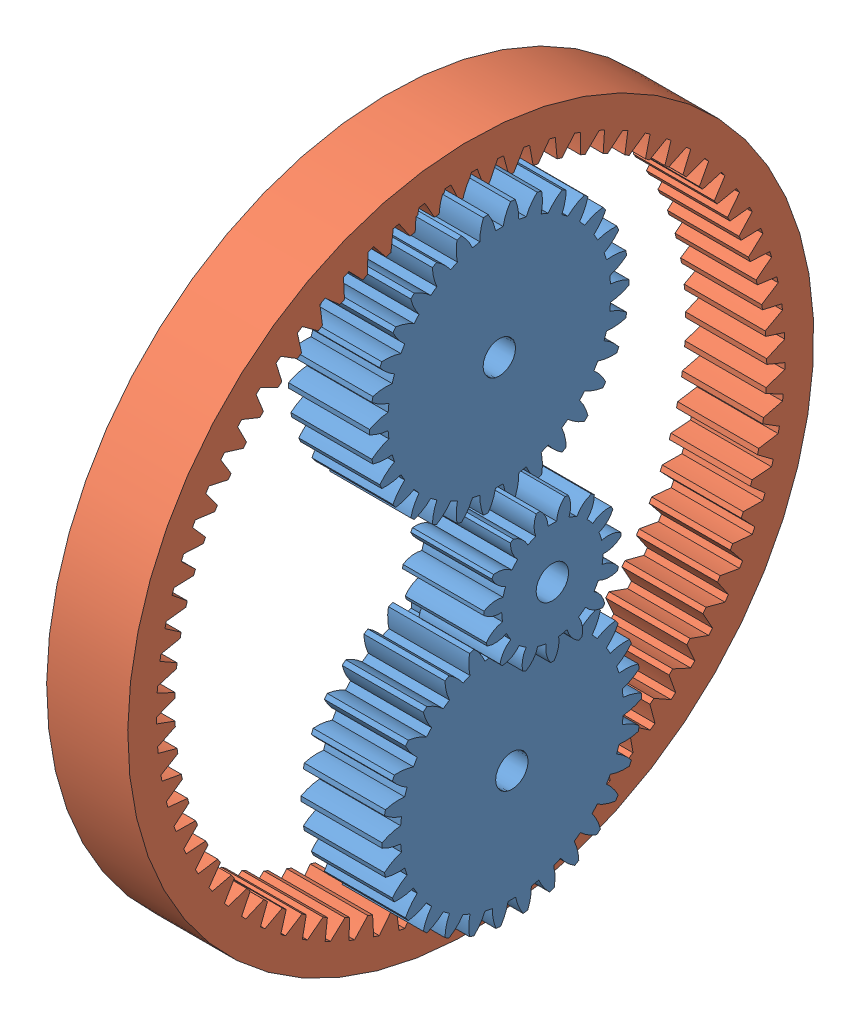
SolidWorks assembly Assem3, configuration Default. Lengths in mm.
Overall size (10 58.23 58.23).
4 component instances, 2 part files, 4 mates.
Components (placement in the parent):
- spur gear_am-1: spur gear_am [Metric - Spur gear 0.5M 15T 20PA 5FW ---S15N75H50L2N] at (-0.0365 -6.3386 28.5198) size (5 8.43 8.47)
- internal spur gear_am-2: internal spur gear_am [Metric - Internal spur gear 0.5M 75T 20PA 5FW ---S75S42.3OD 1AF] at (-0.0365 -6.3452 28.5512) x (-1 0 0) z (0 -0.850414 -0.526114) size (5 42.3 42.3)
- spur gear_am-3: spur gear_am [Metric - Spur gear 0.5M 30T 20PA 5FW ---S30N75H50L2N] at (-2.5182 4.8152 29.308) size (5 15.94 16)
- spur gear_am-4: spur gear_am [Metric - Spur gear 0.5M 30T 20PA 5FW ---S30N75H50L2N] at (-2.5182 -17.6397 28.5353) size (5 15.94 16)
Mates (geometry in assembly coordinates):
- Coincident1: coincident: plane of spur gear_am-1 through (-0.0365 -6.3386 28.5198) normal (-1 0 0); plane of internal spur gear_am-2 through (-0.0365 9.1748 38.1528) normal (1 0 0)
- GearMate1: gear = 2 : 2 mm: circle of spur gear_am-4; circle of spur gear_am-1
- GearMate2: gear = 2 : 2 mm: circle of spur gear_am-1; circle of spur gear_am-3
- GearMate3: gear = 2 : 42.3 mm: circle of internal spur gear_am-2; circle of spur gear_am-1
